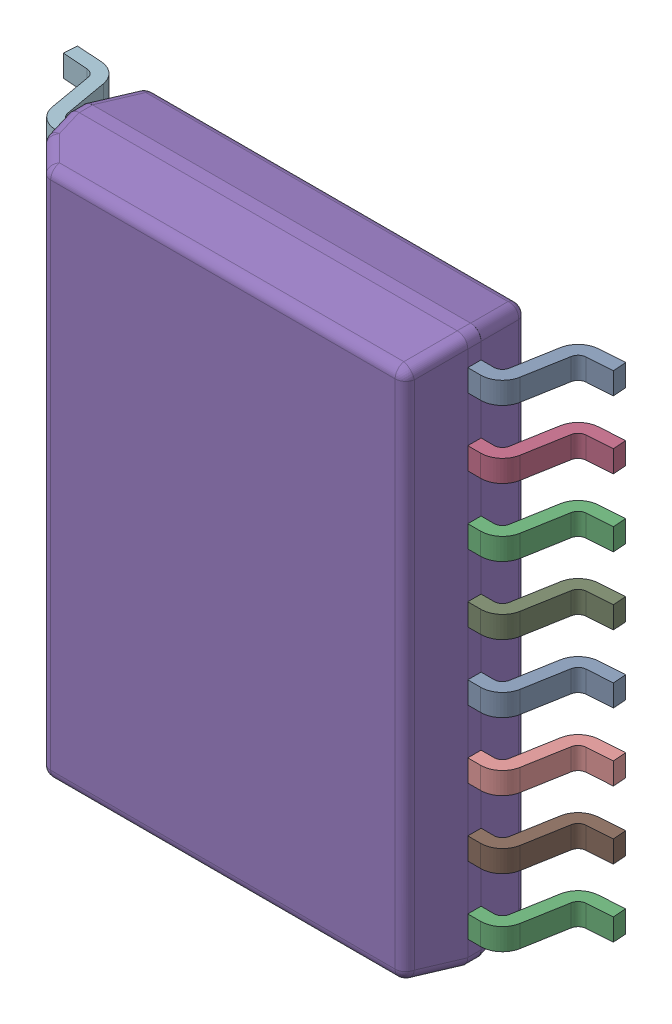
SolidWorks assembly DW0016B_ASM, configuration По умолчанию. Lengths in mm.
Overall size (10.33 10.3 2.59).
17 component instances, 2 part files, 0 mates.
Components (placement in the parent):
- DW0016B_ASM-Part-1-1: DW0016B_ASM-Part-1 [По умолчанию] at (4.315 -0.635 0.25) x (0 1 0) z (1 0 0) size (0.41 1.57 1.42)
- DW0016B_ASM-Part-1-2: DW0016B_ASM-Part-1 [По умолчанию] at (-4.315 -1.905 0.25) x (0 -1 0) z (-1 0 0) size (0.41 1.57 1.42)
- DW0016B_ASM-Part-1-3: DW0016B_ASM-Part-1 [По умолчанию] at (4.315 -4.445 0.25) x (0 1 0) z (1 0 0) size (0.41 1.57 1.42)
- DW0016B_ASM-Part-1-4: DW0016B_ASM-Part-1 [По умолчанию] at (4.315 3.175 0.25) x (0 1 0) z (1 0 0) size (0.41 1.57 1.42)
- DW0016B_ASM-Part-1-5: DW0016B_ASM-Part-1 [По умолчанию] at (-4.315 0.635 0.25) x (0 -1 0) z (-1 0 0) size (0.41 1.57 1.42)
- DW0016B_ASM-Part-1-6: DW0016B_ASM-Part-1 [По умолчанию] at (-4.315 -3.175 0.25) x (0 -1 0) z (-1 0 0) size (0.41 1.57 1.42)
- DW0016B_ASM-Part-1-7: DW0016B_ASM-Part-1 [По умолчанию] at (-4.315 -4.445 0.25) x (0 -1 0) z (-1 0 0) size (0.41 1.57 1.42)
- DW0016B_ASM-Part-1-8: DW0016B_ASM-Part-1 [По умолчанию] at (-4.315 3.175 0.25) x (0 -1 0) z (-1 0 0) size (0.41 1.57 1.42)
- DW0016B_ASM-Part-1-9: DW0016B_ASM-Part-1 [По умолчанию] at (4.315 0.635 0.25) x (0 1 0) z (1 0 0) size (0.41 1.57 1.42)
- DW0016B_ASM-Part-1-10: DW0016B_ASM-Part-1 [По умолчанию] at (4.315 -1.905 0.25) x (0 1 0) z (1 0 0) size (0.41 1.57 1.42)
- DW0016B_ASM-Part-1-11: DW0016B_ASM-Part-1 [По умолчанию] at (4.315 -3.175 0.25) x (0 1 0) z (1 0 0) size (0.41 1.57 1.42)
- DW0016B_ASM-Part-1-12: DW0016B_ASM-Part-1 [По умолчанию] at (-4.315 4.445 0.25) x (0 -1 0) z (-1 0 0) size (0.41 1.57 1.42)
- DW0016B_ASM-Part-1-13: DW0016B_ASM-Part-1 [По умолчанию] at (4.315 4.445 0.25) x (0 1 0) z (1 0 0) size (0.41 1.57 1.42)
- DW0016B_ASM-Part-1-14: DW0016B_ASM-Part-1 [По умолчанию] at (-4.315 1.905 0.25) x (0 -1 0) z (-1 0 0) size (0.41 1.57 1.42)
- DW0016B_ASM-Part-1-15: DW0016B_ASM-Part-1 [По умолчанию] at (4.315 1.905 0.25) x (0 1 0) z (1 0 0) size (0.41 1.57 1.42)
- DW0016B_ASM-Part-1-16: DW0016B_ASM-Part-1 [По умолчанию] at (-4.315 -0.635 0.25) x (0 -1 0) z (-1 0 0) size (0.41 1.57 1.42)
- DW0016B_ASM-Part-2-1: DW0016B_ASM-Part-2 [По умолчанию] at (0 0 1.568) x (0 1 0) z (1 0 0) size (10.3 2.29 7.5)
